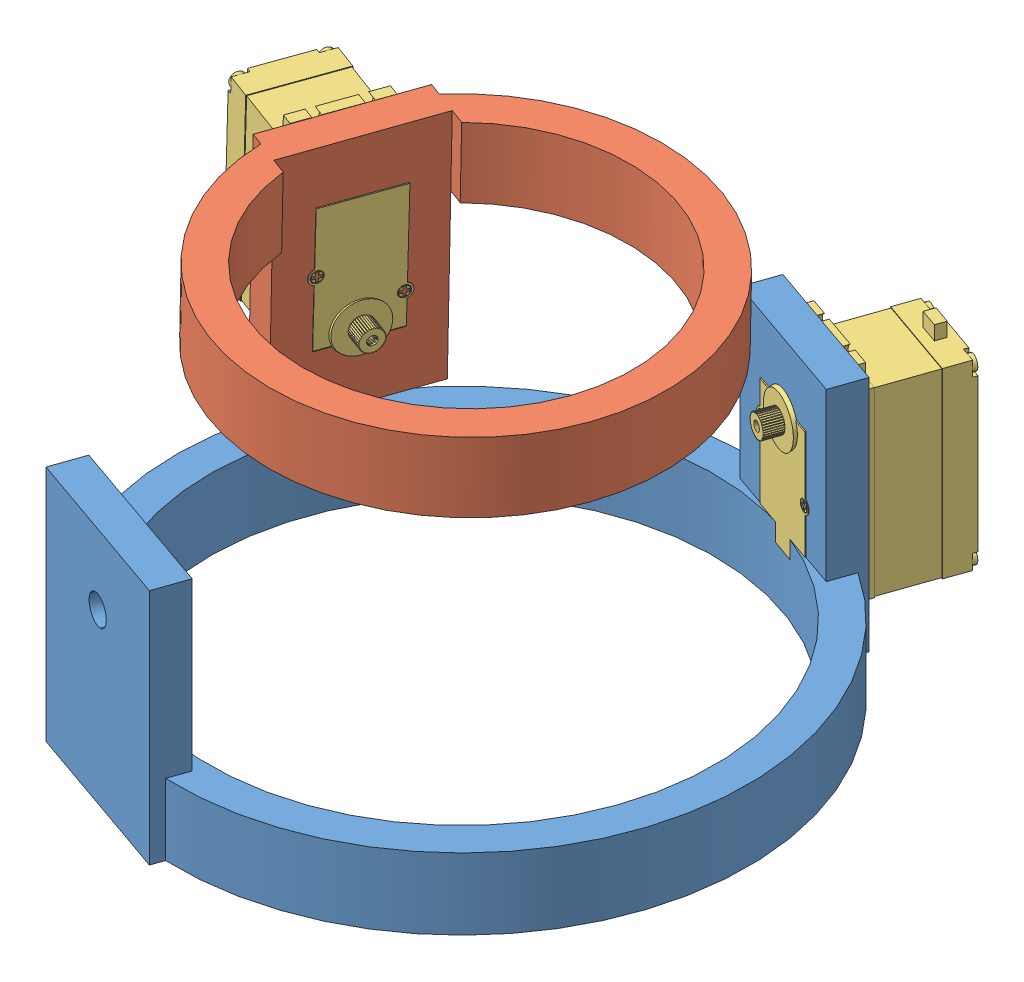
SolidWorks assembly GimbalV8, configuration Default. Lengths in mm.
Overall size (259.83 140.32 264.53).
4 component instances, 3 part files, 8 mates.
Components (placement in the parent):
- Outer_Ring-1: Outer_Ring [Default] at (104.1871 -17.5221 197.5999) x (-0.329537 0 0.944143) z (0.944143 0 0.329537) size (204 84.77 204)
- Inner_Ring-2: Inner_Ring [Default] at (106.6455 118.8968 198.458) x (0.943598 -0.033952 0.329347) z (-0.329537 0 0.944143) size (144 84.77 144)
- 60Kg Servo-1: 60Kg Servo [Default] at (144.2604 23.3514 82.7875) x (0 -1 0) z (-0.944143 0 -0.329537) size (81.92 55.94 30)
- 60Kg Servo-2: 60Kg Servo [Default] at (18.9326 81.1567 167.7287) x (0.033941 0.999407 0.005784) z (0.329348 -0.00572 -0.944191) size (81.92 55.94 30)
Mates (geometry in assembly coordinates):
- Perpendicular2: perpendicular: line of Outer_Ring-1 through (134.0433 42.2484 112.0601) axis (-0.329537 0 0.944143); line of Inner_Ring-2 through (47.5469 61.2183 177.8306) axis (0.943598 -0.033952 0.329347)
- Coincident8: coincident aligned: plane of Outer_Ring-1 through (104.1871 -17.5221 197.5999) normal (-0.329537 0 0.944143); plane of Inner_Ring-2 through (106.6455 118.8968 198.458) normal (-0.329537 0 0.944143)
- Coincident13: coincident: point of Outer_Ring-1; point of Inner_Ring-2
- Coincident14: coincident aligned: line of Outer_Ring-1 through (134.0433 42.2484 112.0601) axis (-0.329537 0 0.944143); line of 60Kg Servo-1 through (131.397 42.2484 119.6421) axis (-0.329537 0 0.944143)
- Coincident16: coincident anti-aligned: plane of Outer_Ring-1 through (137.7999 -17.5221 101.2974) normal (0.329537 0 -0.944143); plane of 60Kg Servo-1 through (123.6377 -17.6086 96.3543) normal (-0.329537 0 0.944143)
- Coincident17: coincident anti-aligned: plane of Outer_Ring-1 through (104.1871 -17.5221 197.5999) normal (0.944143 0 0.329537); plane of 60Kg Servo-1 through (144.2604 23.3514 82.7875) normal (-0.944143 0 -0.329537)
- Coincident18: coincident aligned: line of Inner_Ring-2 through (47.5469 61.2183 177.8306) axis (0.943598 -0.033952 0.329347); line of 60Kg Servo-2 through (55.1246 60.9456 180.4755) axis (0.943598 -0.033952 0.329347)
- Coincident19: coincident anti-aligned: plane of Inner_Ring-2 through (38.7064 121.3413 174.745) normal (-0.943598 0.033952 -0.329347); plane of 60Kg Servo-2 through (43.7623 121.3409 160.2596) normal (0.943598 -0.033952 0.329347)
